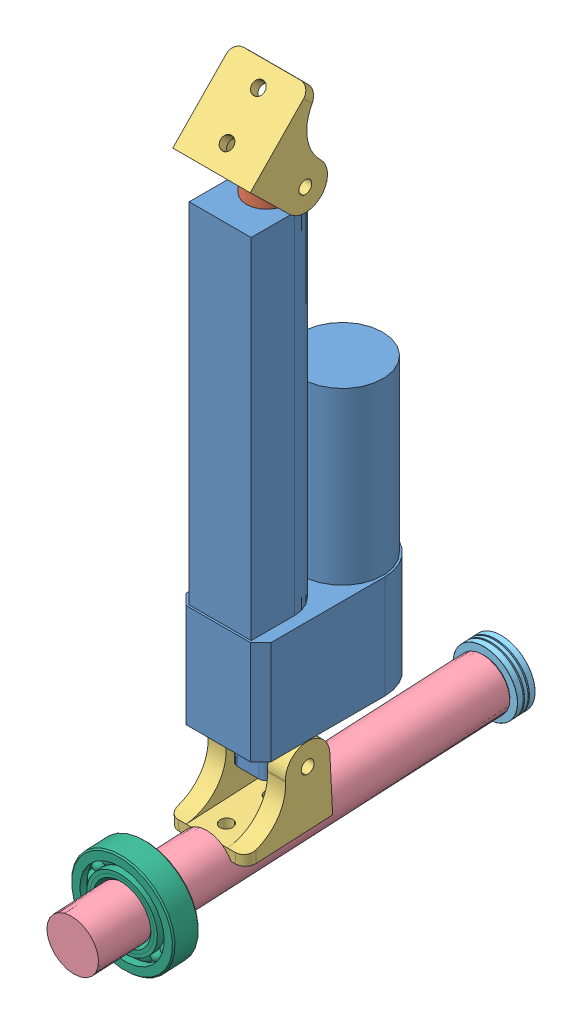
SolidWorks assembly Actuator+Shoulder, configuration Default. Lengths in mm.
Overall size (61.43 355.99 214.74).
8 component instances, 6 part files, 9 mates.
Components (placement in the parent):
- Actuator Draft-1: Actuator Draft [Default] at (-7.6865 -102.2801 28.8302) size (41.91 242.57 82.04)
- Piston draft-1: Piston draft [Default] at (-37.5678 -6.7761 37.6899) x (0 0 -1) z (1 0 0) size (19.81 147.83 19.81)
- Actuator Bracket Draft-1: Actuator Bracket Draft [Default] at (-38.0768 -141.7759 44.4383) x (1 0 0) z (0 -0.05097 0.9987) size (38.1 38.1 42.67)
- Actuator Bracket Draft-2: Actuator Bracket Draft [Default] at (-39.2419 156.964 51.4677) x (1 0 0) z (0 0.716107 -0.69799) size (38.1 38.1 42.67)
- Shoulder Assem Superdraft-1: Shoulder Assem Superdraft [Default] at (52.1718 -342.5098 -119.6542) x (-1 0 0) z (0 0.9987 0.05097) size (61.43 211.89 61.43)
  - Shoulder-Joint Superdraft-1: Shoulder-Joint Superdraft [Default] at (88.5966 40.6015 203.7568) size (25.4 210.82 25.4)
  - 6655K190-1: 6655K190 [6655K19] at (88.5966 36.2581 203.7568) size (31.75 8.69 31.75)
  - 6383K570-1: 6383K570 [6383K57] at (88.5966 213.1472 203.7568) x (0.971277 0 -0.23795) z (0 1 0) size (50.8 50.8 12.7)
Mates (geometry in assembly coordinates):
- Concentric1: concentric anti-aligned: cylinder of Actuator Draft-1 through (-37.5678 -6.7761 37.6899) axis (0 1 0) radius 9.906; cylinder of Piston draft-1 through (-37.5678 120.2239 37.6899) axis (0 -1 0) radius 9.906
- Parallel1: parallel aligned: cylinder of Actuator Draft-1 through (-26.5188 -114.2181 37.6899) axis (-1 0 0) radius 3.81; cylinder of Piston draft-1 through (-21.8198 132.1619 37.6899) axis (-1 0 0) radius 3.81
- Coincident1: coincident anti-aligned: plane of Actuator Draft-1 through (-37.5678 -6.7761 37.6899) normal (0 1 0); plane of Piston draft-1 through (-37.5678 -6.7761 37.6899) normal (0 -1 0)
- Concentric3: concentric anti-aligned: cylinder of Actuator Draft-1 through (-26.5188 -114.2181 37.6899) axis (-1 0 0) radius 3.81; cylinder of Actuator Bracket Draft-1 through (-17.3748 -114.2181 37.6899) axis (1 0 0) radius 3.175
- Concentric4: concentric anti-aligned: cylinder of Piston draft-1 through (-21.8198 132.1619 37.6899) axis (-1 0 0) radius 3.81; cylinder of Actuator Bracket Draft-2 through (-18.5398 132.1619 37.6899) axis (1 0 0) radius 3.175
- Concentric7: concentric aligned: cylinder of Actuator Bracket Draft-1 through (-36.4248 -137.4138 58.6329) axis (0 0.9987 0.05097) radius 3.175; cylinder of Shoulder Assem Superdraft-1/Shoulder-Joint Superdraft-1 through (-36.4248 -167.8541 57.0793) axis (0 0.9987 0.05097) radius 3.175
- Coincident4: coincident anti-aligned: plane of Actuator Bracket Draft-1 through (-38.0768 -141.7759 44.4383) normal (0 -0.9987 -0.05097); plane of Shoulder Assem Superdraft-1/Shoulder-Joint Superdraft-1 through (-61.8248 -142.9791 68.0134) normal (0 0.9987 0.05097)
- Coincident5: coincident anti-aligned: plane of Actuator Bracket Draft-1 through (-55.4748 -137.9057 68.2723) normal (0 -0.05097 0.9987); plane of Shoulder Assem Superdraft-1/Shoulder-Joint Superdraft-1 through (-61.8248 -135.369 68.4018) normal (0 0.05097 -0.9987)
- Coincident6: coincident anti-aligned: plane of Actuator Draft-1 through (-46.5848 -122.3461 32.4829) normal (-1 0 0); plane of Actuator Bracket Draft-1 through (-46.5848 -102.7536 27.3388) normal (1 0 0)
